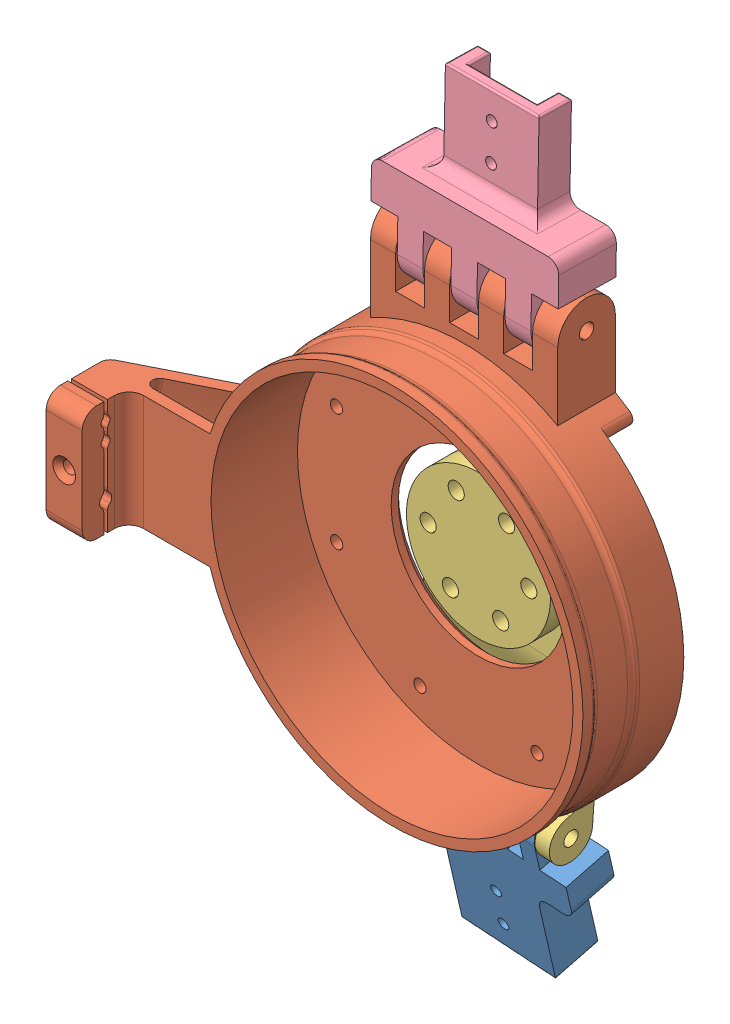
SolidWorks assembly hinge_orthosis_assem, configuration Default. Lengths in mm.
Overall size (136.17 217.51 64.12).
4 component instances, 4 part files, 6 mates.
Components (placement in the parent):
- Lower_Hinge_orthosis-1: Lower_Hinge_orthosis [Default] at (25.7485 -122.2405 -6.9552) x (-0.997757 0.066937 0) z (-0.018084 -0.269554 0.962815) size (46.2 48 12)
- MotorHousingR_v2-1: MotorHousingR_v2 [Default] at (30.4836 -51.6594 0.9359) size (136.17 126 53)
- RotorAttachCanted_v2-1: RotorAttachCanted_v2 [Default] at (30.4836 -51.6594 4.9359) x (-0.997757 0.066937 0) z (0 0 -1) size (40 90 16)
- Upper_hinge_orthosis-1: Upper_hinge_orthosis [Default] at (30.4426 13.3406 0.9359) x (-1 0 0) z (0 -0.019077 -0.999818) size (52 53 16)
Mates (geometry in assembly coordinates):
- Concentric1: concentric aligned: cylinder of MotorHousingR_v2-1 through (-22.5164 13.3406 0.9359) axis (1 0 0) radius 2; cylinder of Upper_hinge_orthosis-1 through (4.4426 13.3406 0.9359) axis (1 0 0) radius 2.1
- Distance1: distance = 0.44 mm anti-aligned: plane of MotorHousingR_v2-1 through (11.4836 21.3406 8.9359) normal (1 0 0); plane of Upper_hinge_orthosis-1 through (11.9236 4.4948 9.1062) normal (-1 0 0)
- Coincident2: coincident aligned: plane of MotorHousingR_v2-1 through (30.4836 -51.6594 4.9359) normal (0 0 1); plane of RotorAttachCanted_v2-1 through (30.4836 -51.6594 4.9359) normal (0 0 1)
- Concentric4: concentric anti-aligned: cylinder of MotorHousingR_v2-1 through (30.4836 -51.6594 39.9359) axis (0 0 -1) radius 22; cylinder of RotorAttachCanted_v2-1 through (30.4836 -51.6594 -1.0641) axis (0 0 1) radius 20
- Concentric8: concentric anti-aligned: cylinder of Lower_Hinge_orthosis-1 through (49.2479 -117.0621 -5.0641) axis (-0.997757 0.066937 0) radius 2.1; cylinder of RotorAttachCanted_v2-1 through (6.2444 -114.1771 -5.0641) axis (0.997757 -0.066937 0) radius 2
- Distance3: distance = 0.2 mm anti-aligned: plane of RotorAttachCanted_v2-1 through (10.2356 -114.4449 -6.0641) normal (0.997757 -0.066937 0); plane of Lower_Hinge_orthosis-1 through (10.5436 -112.8409 -10.841) normal (-0.997757 0.066937 0)
